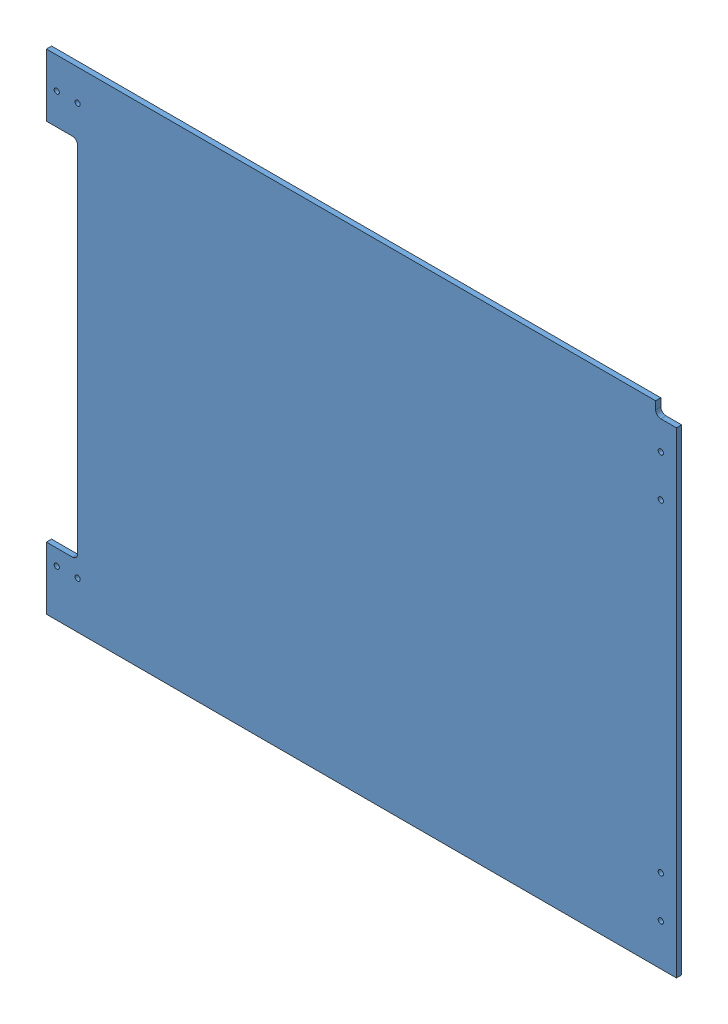
SolidWorks assembly GE-19079-Right-Red, configuration Default. Lengths in mm.
Overall size (768.35 596.9 44.58).
2 component instances, 2 part files, 3 mates.
Components (placement in the parent):
- GE-19079-1: GE-19079 [GE-19079] at origin size (768.35 596.9 6.35)
- GE-19079-Right-Red-Vinyl-1: GE-19079-Right-Red-Vinyl [Notched] at (0 0 6.35) size (768.35 596.9 0.13)
Mates (geometry in assembly coordinates):
- Coincident1: coincident: plane of assembly; plane of assembly; plane of GE-19079-1 through (0 0 6.35) normal (0 0 1); plane of GE-19079-Right-Red-Vinyl-1 through (0 0 6.35) normal (0 0 -1)
- Coincident2: coincident: plane of assembly; plane of assembly; plane of GE-19079-1 through (368.3 -298.45 6.35) normal (1 0 0); plane of GE-19079-Right-Red-Vinyl-1 through (368.3 -298.45 6.477) normal (1 0 0)
- Coincident3: coincident: plane of assembly; plane of assembly; plane of GE-19079-1 through (-368.3 298.45 6.35) normal (0 1 0); plane of GE-19079-Right-Red-Vinyl-1 through (-368.3 298.45 6.477) normal (0 1 0)
